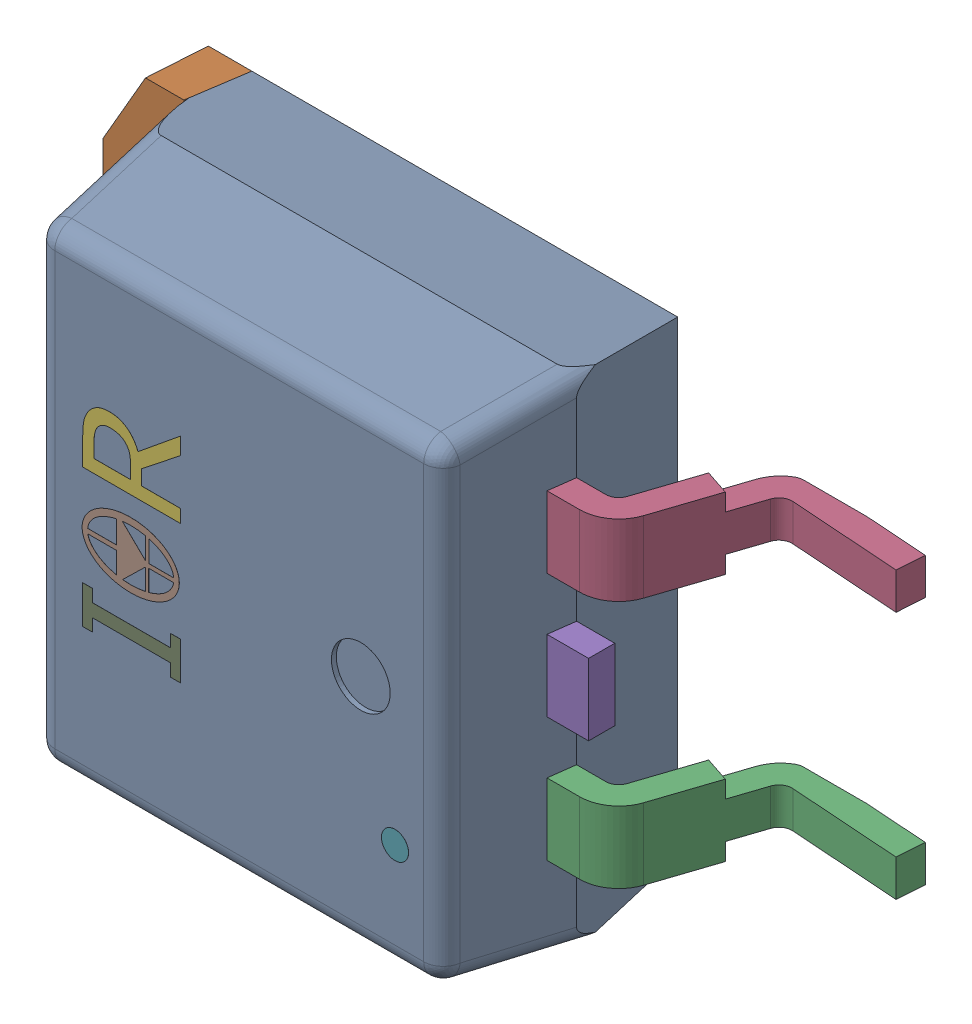
SolidWorks assembly Q1.step, configuration Default. Lengths in mm.
Overall size (15.25 10.16 5.09).
5 component instances, 4 part files, 0 mates.
Components (placement in the parent):
- Trans_Infineon_IRF2805STRLPBF_eec.step-1: Trans_Infineon_IRF2805STRLPBF_eec.step [Default] at (78.456 60.579 0) x (0 1 0) z (0 0 1) size (10.16 15.25 5.09)
  - 1-0.step-1: 1-0.step [Default] at (0 0 2.633) x (1 0 0) z (0 -1 0) size (10.16 4.83 9.02)
  - 2-1.step-1: 2-1.step [Default] at (0 0 2.633) x (1 0 0) z (0 -1 0) size (9.9 1.4 6.86)
  - 3-2.step-1: 3-2.step [Default] at (0 0 2.633) x (1 0 0) z (0 -1 0) size (6.54 3.17 4.65)
  - IRF_logo.step-1: IRF_logo.step [Default] at (1.3993 2.6618 4.985) size (5.32 6.67 0.1)
